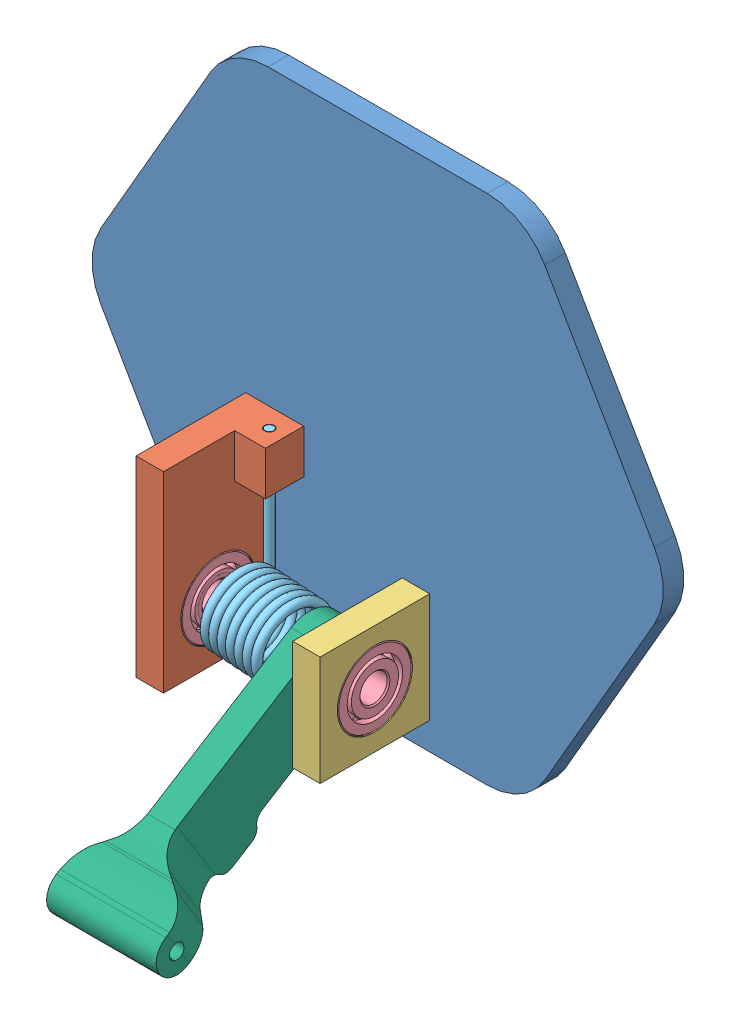
SolidWorks assembly delta_controllerR2.0, configuration Default. Lengths in mm.
Overall size (132.39 140.8 80.08).
7 component instances, 6 part files, 22 mates.
Components (placement in the parent):
- baseplate-1: baseplate [Default] at origin size (132.39 118.78 4.76)
- arm_retainer_large-1: arm_retainer_large [Default] at (-21.8562 -20.5991 7.956) size (13.46 44.45 25.4)
- arm_retainer_small-1: arm_retainer_small [Default] at (0.5673 -24.2922 4.7625) size (6.35 25.4 25.4)
- 6383K120-5: 6383K120 [6383K12] at (-27.4067 -40.3415 17.4625) x (0 0 -1) z (1 0 0) size (17.46 17.46 6.35)
- 6383K120-4: 6383K120 [6383K12] at (8.89 -40.3415 17.4625) x (0 0 1) z (-1 0 0) size (17.46 17.46 6.35)
- spring-2: spring [9287K222] at (-6.5214 -40.9437 17.114) x (0.998831 -0.041874 0.024148) z (-0.041862 -0.499561 0.865266) size (19.3 32.79 61.68)
- lower_armR3-1: lower_armR3 [Default] at (12.7 -69.1573 25.2194) x (0 -0.847952 -0.530073) z (-1 0 0) size (19.05 67.64 25.4)
Mates (geometry in assembly coordinates):
- Coincident6: coincident anti-aligned: plane of baseplate-1 through (25.4 43.9941 4.7625) normal (0 0 1); plane of arm_retainer_small-1 through (0.5673 -24.2922 4.7625) normal (0 0 -1)
- Coincident7: coincident anti-aligned: plane of baseplate-1 through (25.4 43.9941 4.7625) normal (0 0 1); plane of arm_retainer_large-1 through (-21.8562 -20.5991 4.7625) normal (0 0 -1)
- Coincident8: coincident aligned: plane of arm_retainer_large-1 through (-30.5817 -53.0416 30.1625) normal (0 -1 0); plane of arm_retainer_small-1 through (5.715 -53.0416 30.1625) normal (0 -1 0)
- Parallel1: parallel aligned: plane of arm_retainer_large-1 through (-24.2317 -53.0416 30.1625) normal (1 0 0); plane of 6383K120-5 through (-24.2317 -31.9278 17.4625) normal (1 0 0)
- Distance1: distance = 12.7 mm: line of 6383K120-5 through (-30.5817 -40.3415 17.4625) axis (-1 0 0); plane of arm_retainer_large-1 through (-30.5817 -53.0416 30.1625) normal (0 -1 0)
- Distance2: distance = 12.7 mm: line of 6383K120-5 through (-30.5817 -40.3415 17.4625) axis (-1 0 0); plane of arm_retainer_large-1 through (-21.8562 -20.5991 30.1625) normal (0 0 1)
- Coincident12: coincident aligned: plane of arm_retainer_large-1 through (-24.2317 -53.0416 30.1625) normal (1 0 0); plane of 6383K120-5 through (-24.2317 -31.9278 17.4625) normal (1 0 0)
- Parallel2: parallel aligned: plane of arm_retainer_small-1 through (5.715 -53.0416 30.1625) normal (-1 0 0); plane of 6383K120-4 through (5.715 -31.9278 17.4625) normal (-1 0 0)
- Coincident14: coincident anti-aligned: line of 6383K120-5 through (-30.5817 -40.3415 17.4625) axis (-1 0 0); line of 6383K120-4 through (12.065 -40.3415 17.4625) axis (1 0 0)
- Coincident15: coincident aligned: plane of arm_retainer_small-1 through (5.715 -53.0416 30.1625) normal (-1 0 0); plane of 6383K120-4 through (5.715 -31.9278 17.4625) normal (-1 0 0)
- Coincident16: coincident aligned: line of spring-2 through (-305.4952 -40.3415 17.4625) axis (1 0 0); line of 6383K120-4 through (12.065 -40.3415 17.4625) axis (1 0 0)
- Coincident17: coincident anti-aligned: line of spring-2 through (-305.4952 -40.3415 17.4625) axis (1 0 0); line of 6383K120-5 through (-30.5817 -40.3415 17.4625) axis (-1 0 0)
- Parallel3: parallel aligned: plane of arm_retainer_large-1 through (-30.5817 -8.5915 30.1625) normal (0 1 0); plane of spring-2 through (-30.5817 -8.5915 30.1625) normal (0 1 0)
- Distance3: distance = 2.54 mm anti-aligned: cylinder of spring-2 through (-20.7011 -5.7897 9.149) axis (0 -1 0) radius 0.9906; plane of arm_retainer_large-1 through (-24.2317 -53.0416 30.1625) normal (1 0 0)
- Parallel5: parallel aligned: plane of baseplate-1 through (-25.4 -59.3916 4.7625) normal (0 -1 0); plane of arm_retainer_large-1 through (-30.5817 -53.0416 30.1625) normal (0 -1 0)
- Distance6: distance = 6.35 mm aligned: plane of arm_retainer_small-1 through (5.715 -53.0416 30.1625) normal (0 -1 0); plane of baseplate-1 through (-25.4 -59.3916 4.7625) normal (0 -1 0)
- Parallel6: parallel anti-aligned: plane of arm_retainer_large-1 through (-21.8562 -20.5991 30.1625) normal (0 0 1); plane of 6383K120-5 through (-27.4067 -40.3415 17.4625) normal (0 0 -1)
- Parallel7: parallel aligned: plane of arm_retainer_small-1 through (0.5673 -24.2922 30.1625) normal (0 0 1); plane of 6383K120-4 through (8.89 -40.3415 17.4625) normal (0 0 1)
- Coincident26: coordinate: point of baseplate-1; point of assembly
- Distance8: distance = 2.54 mm anti-aligned: plane of lower_armR3-1 through (3.175 -45.1941 40.1994) normal (1 0 0); plane of arm_retainer_small-1 through (5.715 -53.0416 30.1625) normal (-1 0 0)
- Distance9: distance = 2.54 mm anti-aligned: plane of lower_armR3-1 through (-3.175 -45.1941 40.1994) normal (-1 0 0); cylinder of spring-2 through (-6.7056 -68.1488 48.9158) axis (0 0.500877 -0.865519) radius 0.9906
- Coincident27: coincident: plane of lower_armR3-1 through (0 -69.1573 25.2194) normal (-1 0 0); point of assembly
